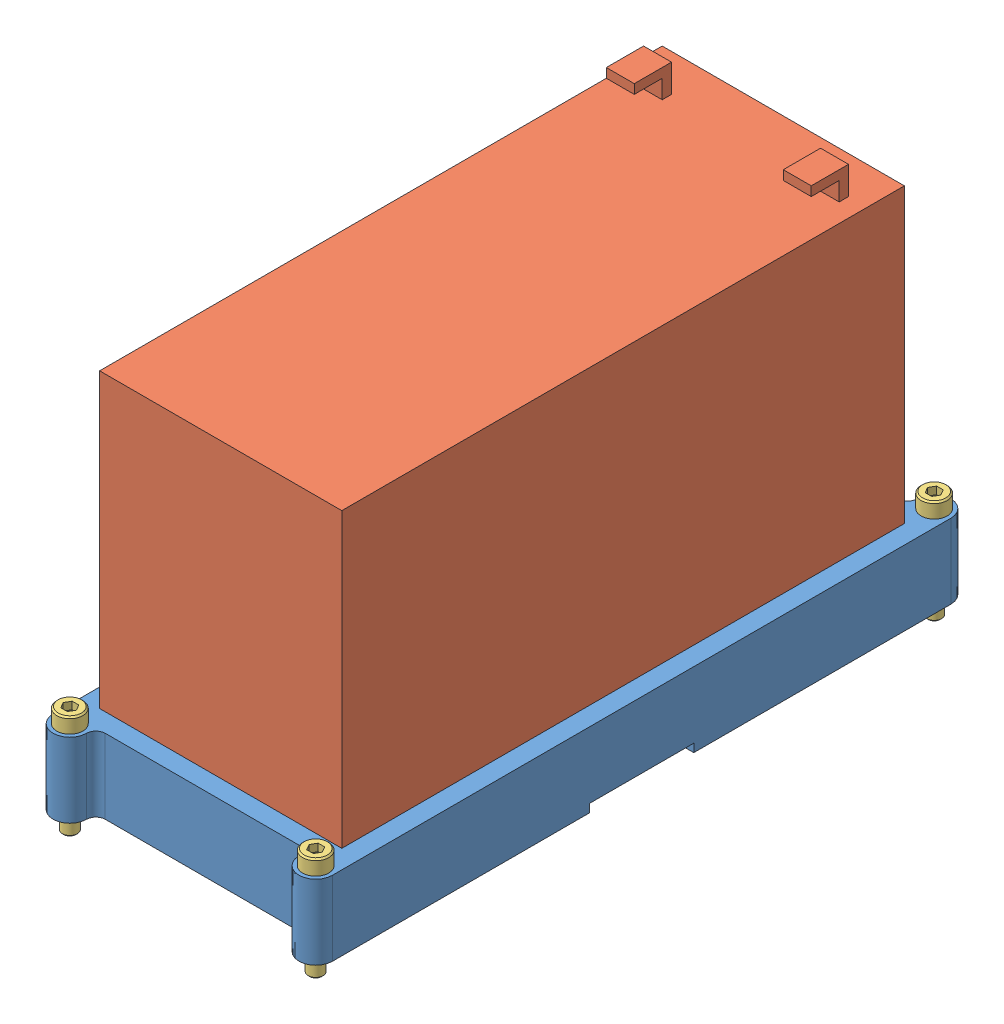
SolidWorks assembly E-02-00, configuration Default. Lengths in mm.
Overall size (75 111 175).
6 component instances, 3 part files, 11 mates.
Components (placement in the parent):
- E-02-02-1: E-02-02 [Default] at (70.7211 76.075 126.038) size (75 20 175)
- E-02-01-2: E-02-01 [Default] at (38.2211 127.075 126.038) x (0 0 1) z (-1 0 0) size (151 102.5 65)
- socket head cap screw_am-2: socket head cap screw_am [B18.3.1M - 4 x 0.7 x 25 Hex SHCS -- 25NHX] at (37.7211 100.075 209.038) x (0 -1 0) z (0 0 1) size (29 7 7)
- socket head cap screw_am-3: socket head cap screw_am [B18.3.1M - 4 x 0.7 x 25 Hex SHCS -- 25NHX] at (103.7211 100.075 209.038) x (0 -1 0) z (0 0 1) size (29 7 7)
- socket head cap screw_am-4: socket head cap screw_am [B18.3.1M - 4 x 0.7 x 25 Hex SHCS -- 25NHX] at (37.7211 100.075 43.038) x (0 -1 0) z (0 0 1) size (29 7 7)
- socket head cap screw_am-6: socket head cap screw_am [B18.3.1M - 4 x 0.7 x 25 Hex SHCS -- 25NHX] at (103.7211 100.075 43.038) x (0 -1 0) z (0 0 1) size (29 7 7)
Mates (geometry in assembly coordinates):
- Coincident1: coincident anti-aligned: plane of Battery Holder-1 through (103.2211 96.075 201.538) normal (0 0 -1); plane of E-02-01-2 through (103.2211 174.575 201.538) normal (0 0 1)
- Coincident2: coincident anti-aligned: plane of Battery Holder-1 through (70.7211 79.575 126.038) normal (0 1 0); plane of E-02-01-2 through (103.2211 79.575 50.538) normal (0 -1 0)
- Coincident3: coincident anti-aligned: plane of Battery Holder-1 through (38.2211 96.075 201.538) normal (1 0 0); plane of E-02-01-2 through (38.2211 127.075 126.038) normal (-1 0 0)
- Concentric1: concentric anti-aligned: cylinder of E-02-02-1 through (37.7211 96.075 209.038) axis (0 -1 0) radius 2.75; cylinder of socket head cap screw_am-2 through (37.7211 131.825 209.038) axis (0 1 0) radius 3.5
- Coincident4: coincident anti-aligned: plane of E-02-02-1 through (103.7211 96.075 209.038) normal (0 1 0); plane of socket head cap screw_am-2 through (41.2211 96.075 209.038) normal (0 -1 0)
- Concentric2: concentric anti-aligned: cylinder of E-02-02-1 through (103.7211 96.075 209.038) axis (0 -1 0) radius 2.75; cylinder of socket head cap screw_am-3 through (103.7211 131.825 209.038) axis (0 1 0) radius 3.5
- Coincident5: coincident anti-aligned: plane of E-02-02-1 through (103.7211 96.075 209.038) normal (0 1 0); plane of socket head cap screw_am-3 through (107.2211 96.075 209.038) normal (0 -1 0)
- Concentric3: concentric anti-aligned: cylinder of E-02-02-1 through (37.7211 96.075 43.038) axis (0 -1 0) radius 2.75; cylinder of socket head cap screw_am-4 through (37.7211 131.825 43.038) axis (0 1 0) radius 3.5
- Coincident6: coincident anti-aligned: plane of E-02-02-1 through (103.7211 96.075 209.038) normal (0 1 0); plane of socket head cap screw_am-4 through (41.2211 96.075 43.038) normal (0 -1 0)
- Concentric4: concentric anti-aligned: cylinder of E-02-02-1 through (103.7211 96.075 43.038) axis (0 -1 0) radius 2.75; cylinder of socket head cap screw_am-6 through (103.7211 131.825 43.038) axis (0 1 0) radius 3.5
- Coincident8: coincident anti-aligned: plane of E-02-02-1 through (103.7211 96.075 209.038) normal (0 1 0); plane of socket head cap screw_am-6 through (107.2211 96.075 43.038) normal (0 -1 0)
